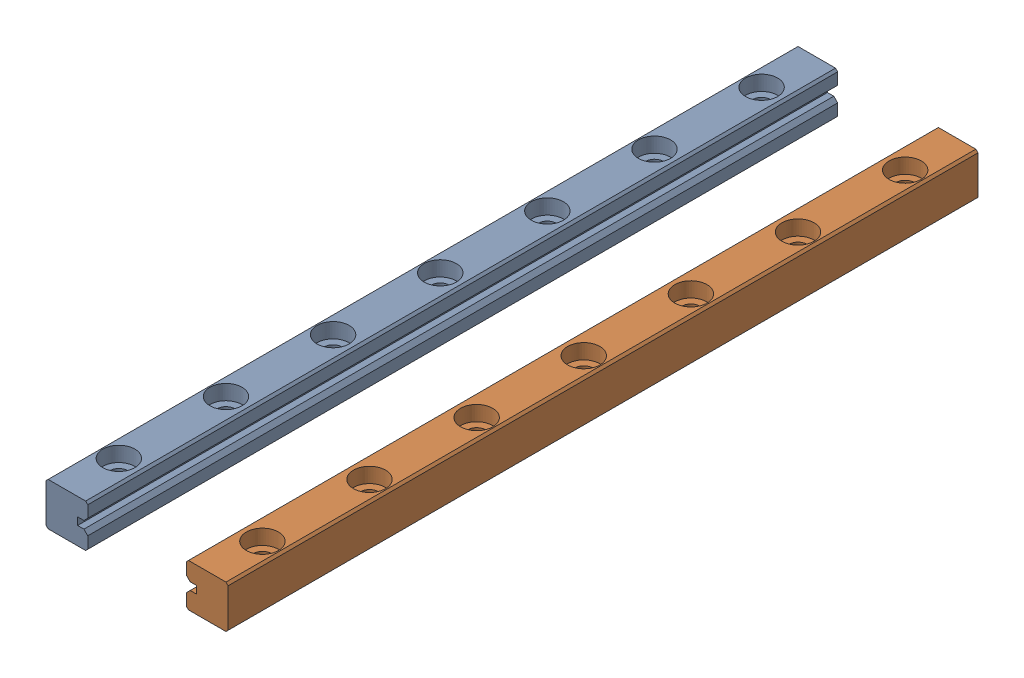
SolidWorks assembly Führung_1770_nm, configuration Default. Lengths in mm.
Overall size (17 4 70).
2 component instances, 1 part files, 0 mates.
Components (placement in the parent):
- Schiene_1770-1: Schiene_1770 [Default] at (-4.4089 -1.3882 35) size (3.9 4 70)
- Schiene_1770-2: Schiene_1770 [Default] at (12.5911 -1.3882 -35) x (-1 0 0) z (0 0 -1) size (3.9 4 70)
